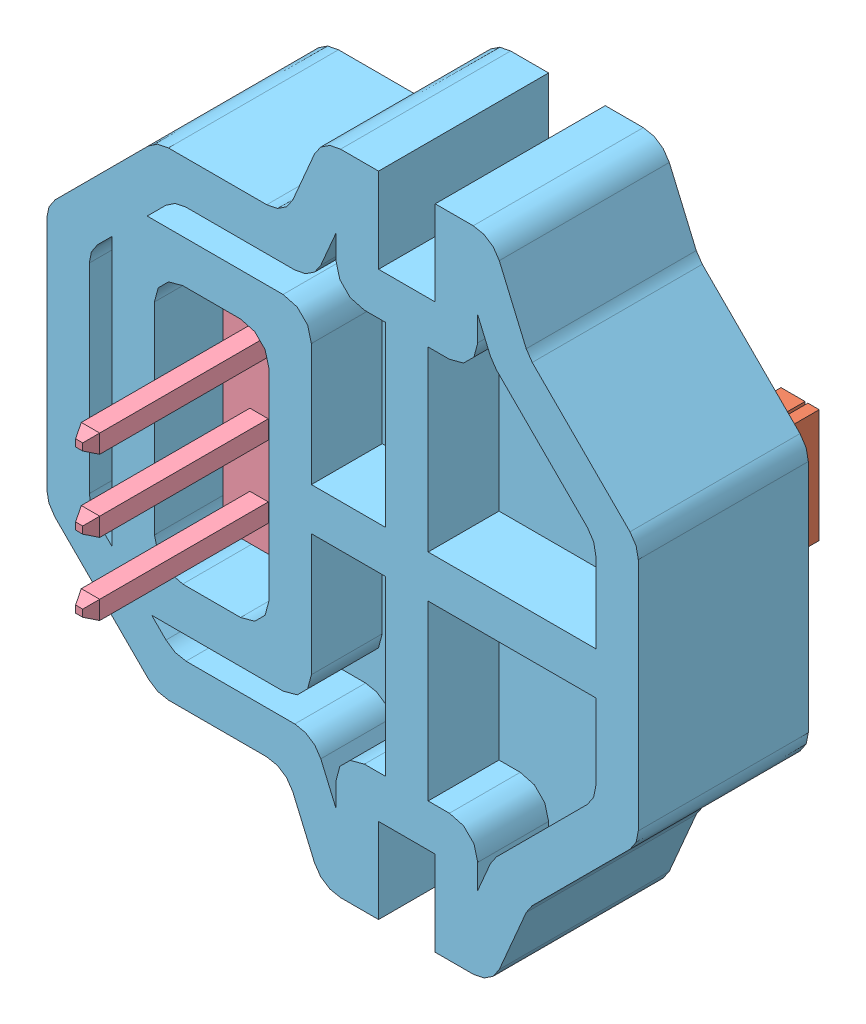
SolidWorks assembly Assemblage phototrans, configuration Défaut. Lengths in mm.
Overall size (20.87 22.87 14.49).
7 component instances, 5 part files, 13 mates.
Components (placement in the parent):
- schema phototrans-1: schema phototrans [Défaut] at origin size (17.87 13.87 1.6)
- ee-sx1320-1: ee-sx1320 [Default] at (12.7 5.08 0) x (-1 0 0) z (0 -1 0) size (5.1 4 4)
- Resistor 1206-1: Resistor 1206 [Default] at (11.43 10.16 -0.03) x (1 0 0) z (0 1 0) size (3.2 0.56 1.66)
- Resistor 1206-2: Resistor 1206 [Default] at (7.239 6.223 -0.03) x (0 1 0) z (-1 0 0) size (3.2 0.56 1.66)
- 3-Pin Header - Male - 2.54mm.step-2: 3-Pin Header - Male - 2.54mm.step [Default] at (3.625 2.355 1.6) x (0 1 0) z (0 0 1) size (7.62 2.54 11.94)
  - 3-Pin Header - Male - 2.54mm.step-1: 3-Pin Header - Male - 2.54mm.step [Défaut] x (1 0 0) z (0 -1 0) size (7.62 11.94 2.54)
- Piece plastique-1: Piece plastique [Défaut] x (-1 0 0) z (0 0 -1) size (20.87 22.87 7.2)
Mates (geometry in assembly coordinates):
- Coïncidente1: coincident anti-aligned: plane of schema phototrans-1 through (0 0 0) normal (0 0 -1); plane of ee-sx1320-1 through (10.65 3.08 0) normal (0 0 1)
- Tangent1: tangent aligned: cylinder of schema phototrans-1 through (3.81 2.54 1.6) axis (0 0 -1) radius 0.51; plane of 3-Pin Header - Male - 2.54mm.step-2/3-Pin Header - Male - 2.54mm.step-1 through (3.625 2.03 1.6) normal (0 -1 0)
- Tangent2: tangent aligned: cylinder of schema phototrans-1 through (3.81 2.54 1.6) axis (0 0 -1) radius 0.51; plane of 3-Pin Header - Male - 2.54mm.step-2/3-Pin Header - Male - 2.54mm.step-1 through (3.3 2.03 -1.448) normal (-1 0 0)
- Parallèle1: parallel aligned: plane of schema phototrans-1 through (-0.508 -1.778 1.6) normal (0 -1 0); plane of 3-Pin Header - Male - 2.54mm.step-2/3-Pin Header - Male - 2.54mm.step-1 through (2.609 1.085 1.6) normal (0 -1 0)
- Coïncidente3: coincident anti-aligned: plane of schema phototrans-1 through (0 0 1.6) normal (0 0 1); plane of 3-Pin Header - Male - 2.54mm.step-2/3-Pin Header - Male - 2.54mm.step-1 through (3.625 2.355 1.6) normal (0 0 -1)
- Verrouiller1: lock: unknown of schema phototrans-1; unknown of Resistor 1206-2
- Verrouiller2: lock: unknown of schema phototrans-1; unknown of Resistor 1206-1
- Distance1: distance = 6.858 mm: point of ee-sx1320-1; plane of schema phototrans-1 through (-0.508 -1.778 1.6) normal (0 -1 0)
- Distance2: distance = 13.208 mm: plane of schema phototrans-1 through (-0.508 12.095 1.6) normal (-1 0 0); point of ee-sx1320-1
- Sur place1: in place: plane of schema phototrans-1 through (0 0 0) normal (0 0 -1); plane of Piece plastique-1 through (0 0 0) normal (0 0 -1); moOrthogonalPlaneRef_w of schema phototrans-1 through (0 0 0) normal (0 0 -1); plane of Piece plastique-1 through (0 0 0) normal (0 1 0); plane of schema phototrans-1 through (0 0 0) normal (0 0 -1); plane of Piece plastique-1 through (0 0 0) normal (-1 0 0); plane of schema phototrans-1 through (0 0 0) normal (0 0 -1); unknown of Piece plastique-1
- Coïncidente6: coincident aligned: plane of schema phototrans-1; plane of Piece plastique-1
- Coïncidente7: coincident aligned: moOrthogonalPlaneRef_w of schema phototrans-1 through (0 0 0) normal (0 1 0); plane of Piece plastique-1 through (0 0 0) normal (0 1 0)
- Coïncidente8: coincident anti-aligned: moOrthogonalPlaneRef_w of schema phototrans-1 through (0 0 0) normal (1 0 0); plane of Piece plastique-1 through (0 0 0) normal (-1 0 0)
